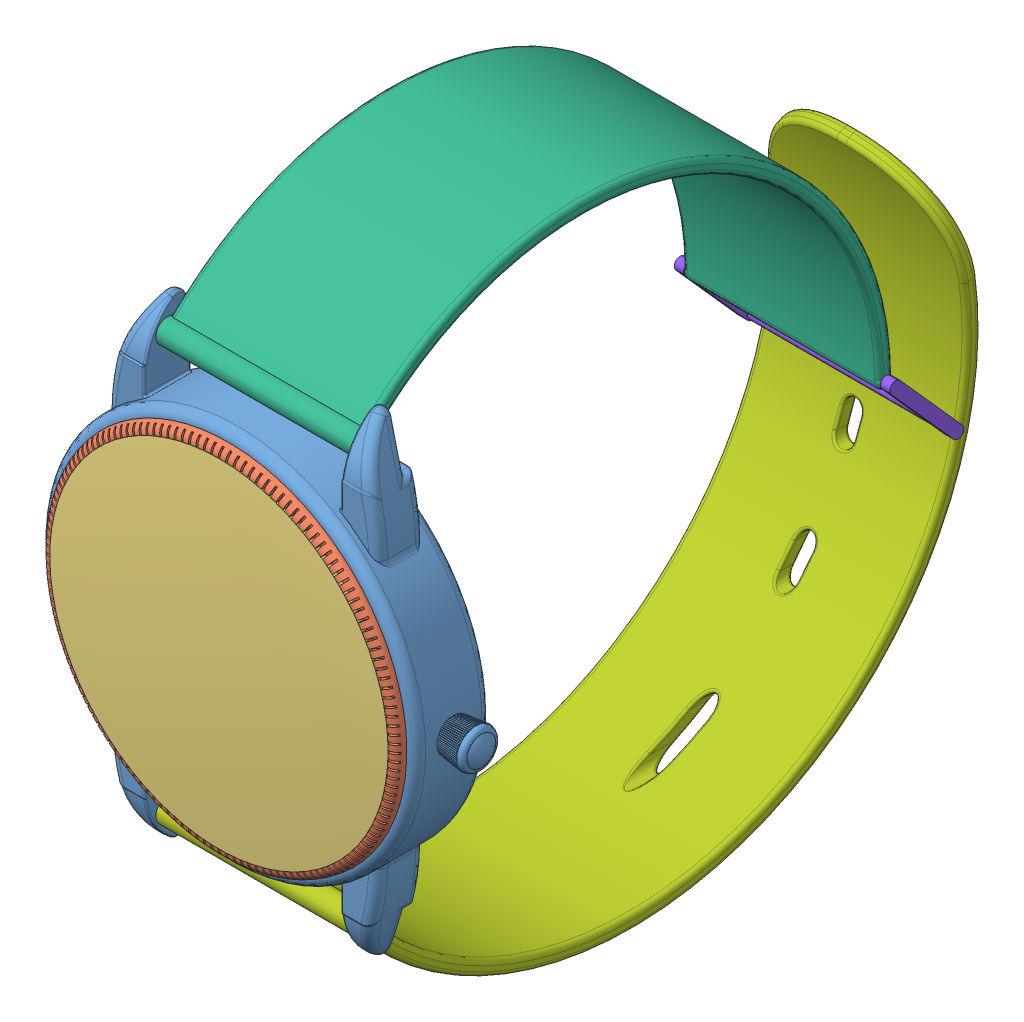
SolidWorks assembly sat rucni muski bez narukvice, configuration Default. Lengths in mm.
Overall size (43.55 70.14 71.71).
8 component instances, 8 part files, 26 mates.
Components (placement in the parent):
- sat telo-1: sat telo [Default] at (-4.6057 -14.8149 12.4954) size (43.55 50.43 8.01)
- Part10-1: Part10 [Default] at (-4.6057 0 0) x (0 0 -1) z (1 0 0) size (1.07 38.1 38.1)
- sat staklo-1: sat staklo [Default] at (-4.6057 0 0) x (0 0 -1) z (1 0 0) size (1.4 36.1 36.1)
- sat ledja-1: sat ledja [Default] at (-4.6057 -14.8149 8.4954) x (-1 0 0) z (0 0 -1) size (36.1 36.1 0.5)
- eta_asm-1: eta_asm [Default] at (-4.6057 5.1851 11.4954) x (0.025743 -0.999669 0) z (0 0 1) size (24 30.7 3.36)
- narukvica sa kopcom-1: narukvica sa kopcom [Default] at (-4.6057 0 0) x (0 0 -1) z (1 0 0) size (57.73 33.73 21.07)
- narukvica sa rupama-1: narukvica sa rupama [Default] at (-4.6057 0 0) x (0 0 -1) z (1 0 0) size (67.06 52.52 22.15)
- kopca 1-1: kopca 1 [Default] at (5.8943 0 0) x (0 0 -1) z (1 0 0) size (8.18 8.73 23)
Mates (geometry in assembly coordinates):
- InPlace1: in place: plane of ? through (-4.6057 0 0) normal (1 0 0); moOrthogonalPlaneRef_w of ? through (-55 -4.6057 0) axis (0 0 1); plane of ? through (-4.6057 0 0) normal (0 0 -1); unknown of ?
- Coincident1: coincident aligned: plane of Part10-1; plane of assembly
- Coincident2: coincident aligned: line of ? through (-21.0623 -4.6057 0) axis (0 0 1)
- Coincident3: coincident anti-aligned: plane of ? through (-4.6057 0 0) normal (0 0 -1)
- InPlace2: in place: plane of ? through (-4.6057 0 0) normal (1 0 0); line of ? through (-55 -4.6057 0) axis (0 0 1); plane of ? through (-4.6057 0 0) normal (0 0 -1); unknown of ?
- Coincident4: coincident aligned: plane of sat staklo-1; plane of assembly
- Coincident5: coincident aligned: line of ? through (-19.8523 -4.6057 0) axis (0 0 1)
- Coincident6: coincident anti-aligned: plane of ? through (-4.6057 0 0) normal (0 0 -1)
- InPlace3: in place: plane of sat telo-1 through (-4.6057 5.1851 8.4954) normal (0 0 -1); plane of ? through (0 0 8.4954) normal (0 0 -1); plane of sat telo-1 through (-4.6057 5.1851 8.4954) normal (0 0 -1); unknown of ?; plane of sat telo-1 through (-4.6057 5.1851 8.4954) normal (0 0 -1); plane of ? through (0 0 8.4954) normal (-1 0 0); plane of sat telo-1 through (-4.6057 5.1851 8.4954) normal (0 0 -1); unknown of sat ledja-1
- Coincident7: coincident aligned: plane of sat telo-1; plane of sat ledja-1
- Coincident8: coincident aligned: moOrthogonalPlaneRef_w of sat telo-1 through (-4.6057 -14.8149 8.4954) normal (0 1 0); plane of sat ledja-1
- Coincident9: coincident anti-aligned: moOrthogonalPlaneRef_w of sat telo-1 through (-4.6057 -14.8149 8.4954) normal (1 0 0); plane of sat ledja-1 through (-4.6057 -14.8149 8.4954) normal (-1 0 0)
- Distance1: distance = 3 mm anti-aligned: plane of sat ledja-1 through (-4.6057 5.1851 8.4954) normal (0 0 1); plane of eta_asm-1 through (-4.6057 5.1851 11.4954) normal (0 0 -1)
- Concentric1: concentric aligned: circle of sat ledja-1; circle of eta_asm-1
- InPlace4: in place: plane of ? through (-4.6057 0 0) normal (1 0 0); line of ? through (-55 -4.6057 0) axis (0 0 1); plane of ? through (-4.6057 0 0) normal (0 0 -1); unknown of ?
- Coincident2: coincident aligned: plane of narukvica sa kopcom-1; plane of assembly
- Coincident3: coincident aligned: line of ? through (-11.5889 -4.6057 0) axis (0 0 1)
- Coincident4: coincident anti-aligned: plane of ? through (-4.6057 0 0) normal (0 0 -1)
- InPlace5: in place: plane of ? through (-4.6057 0 0) normal (1 0 0); line of ? through (-55 -4.6057 0) axis (0 0 1); plane of ? through (-4.6057 0 0) normal (0 0 -1); unknown of ?
- Coincident1: coincident aligned: plane of narukvica sa rupama-1; plane of assembly
- Coincident2: coincident aligned: line of ? through (-12.1829 -4.6057 0) axis (0 0 1)
- Coincident3: coincident anti-aligned: plane of ? through (-4.6057 0 0) normal (0 0 -1)
- InPlace6: in place: plane of ? through (5.8943 22.2629 14.9954) normal (1 0 0); plane of kopca 1-1 through (5.8943 0 0) normal (1 0 0); plane of ? through (5.8943 22.2629 14.9954) normal (1 0 0); line of kopca 1-1 through (-55 5.8943 0) axis (0 0 1); plane of ? through (5.8943 22.2629 14.9954) normal (1 0 0); plane of kopca 1-1 through (5.8943 0 0) normal (0 0 -1); plane of ? through (5.8943 22.2629 14.9954) normal (1 0 0); unknown of kopca 1-1
- Coincident4: coincident aligned: plane of narukvica sa kopcom-1; plane of kopca 1-1
- Coincident5: coincident aligned: moOrthogonalPlaneRef_w of narukvica sa kopcom-1 through (5.8943 0 0) normal (0 1 0); plane of kopca 1-1
- Coincident6: coincident anti-aligned: moOrthogonalPlaneRef_w of narukvica sa kopcom-1 through (5.8943 0 0) normal (0 0 1); plane of kopca 1-1 through (5.8943 0 0) normal (0 0 -1)
